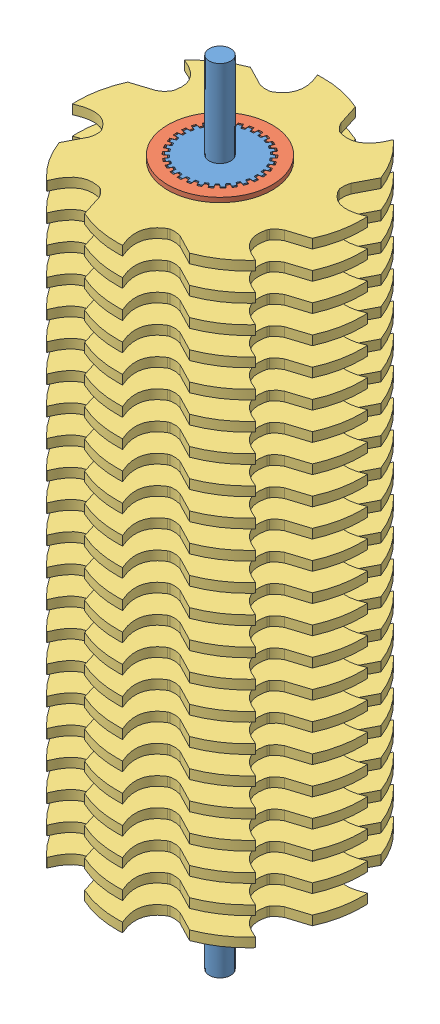
SolidWorks assembly Secondary Grinder Ungeared Blade Assembly, configuration Default. Lengths in mm.
Overall size (84.1 270.26 84.1).
46 component instances, 4 part files, 8 mates.
Components (placement in the parent):
- Secondary Grinder Ungeared Axle-1: Secondary Grinder Ungeared Axle [Default] at (84.7732 71.1932 255.0164) size (26.78 270.26 26.83)
- Secondary Grinder Thin Spacer-1: Secondary Grinder Thin Spacer [Default] at (84.7732 280.7432 255.0164) size (35.56 1.59 35.56)
- Secondary Grinder Blade-34: Secondary Grinder Blade [Default] at (84.7732 276.5099 255.0164) size (84.1 3.17 84.1)
- Secondary Grinder Spacer-34: Secondary Grinder Spacer [Default] at (84.7732 271.2182 255.0164) x (-0.809017 0 0.587785) z (-0.587785 0 -0.809017) size (35.56 6.35 35.56)
- Secondary Grinder Blade-35: Secondary Grinder Blade [Default] at (84.7732 266.9849 255.0164) size (84.1 3.17 84.1)
- Secondary Grinder Blade-36: Secondary Grinder Blade [Default] at (84.7732 257.4599 255.0164) size (84.1 3.17 84.1)
- Secondary Grinder Blade-37: Secondary Grinder Blade [Default] at (84.7732 247.9349 255.0164) size (84.1 3.17 84.1)
- Secondary Grinder Blade-38: Secondary Grinder Blade [Default] at (84.7732 238.4099 255.0164) size (84.1 3.17 84.1)
- Secondary Grinder Blade-39: Secondary Grinder Blade [Default] at (84.7732 228.8849 255.0164) size (84.1 3.17 84.1)
- Secondary Grinder Blade-40: Secondary Grinder Blade [Default] at (84.7732 219.3599 255.0164) size (84.1 3.17 84.1)
- Secondary Grinder Blade-41: Secondary Grinder Blade [Default] at (84.7732 209.8349 255.0164) size (84.1 3.17 84.1)
- Secondary Grinder Blade-42: Secondary Grinder Blade [Default] at (84.7732 200.3099 255.0164) size (84.1 3.17 84.1)
- Secondary Grinder Blade-43: Secondary Grinder Blade [Default] at (84.7732 190.7849 255.0164) size (84.1 3.17 84.1)
- Secondary Grinder Blade-44: Secondary Grinder Blade [Default] at (84.7732 181.2599 255.0164) size (84.1 3.17 84.1)
- Secondary Grinder Blade-45: Secondary Grinder Blade [Default] at (84.7732 171.7349 255.0164) size (84.1 3.17 84.1)
- Secondary Grinder Blade-46: Secondary Grinder Blade [Default] at (84.7732 162.2099 255.0164) size (84.1 3.17 84.1)
- Secondary Grinder Blade-47: Secondary Grinder Blade [Default] at (84.7732 152.6849 255.0164) size (84.1 3.17 84.1)
- Secondary Grinder Blade-48: Secondary Grinder Blade [Default] at (84.7732 143.1599 255.0164) size (84.1 3.17 84.1)
- Secondary Grinder Blade-49: Secondary Grinder Blade [Default] at (84.7732 133.6349 255.0164) size (84.1 3.17 84.1)
- Secondary Grinder Blade-50: Secondary Grinder Blade [Default] at (84.7732 124.1099 255.0164) size (84.1 3.17 84.1)
- Secondary Grinder Blade-51: Secondary Grinder Blade [Default] at (84.7732 114.5849 255.0164) size (84.1 3.17 84.1)
- Secondary Grinder Blade-52: Secondary Grinder Blade [Default] at (84.7732 105.0599 255.0164) size (84.1 3.17 84.1)
- Secondary Grinder Blade-53: Secondary Grinder Blade [Default] at (84.7732 95.5349 255.0164) size (84.1 3.17 84.1)
- Secondary Grinder Blade-54: Secondary Grinder Blade [Default] at (84.7732 86.0099 255.0164) size (84.1 3.17 84.1)
- Secondary Grinder Blade-55: Secondary Grinder Blade [Default] at (84.7732 76.4849 255.0164) size (84.1 3.17 84.1)
- Secondary Grinder Spacer-35: Secondary Grinder Spacer [Default] at (84.7732 261.6932 255.0164) x (-0.809017 0 0.587785) z (-0.587785 0 -0.809017) size (35.56 6.35 35.56)
- Secondary Grinder Spacer-36: Secondary Grinder Spacer [Default] at (84.7732 252.1682 255.0164) x (-0.809017 0 0.587785) z (-0.587785 0 -0.809017) size (35.56 6.35 35.56)
- Secondary Grinder Spacer-37: Secondary Grinder Spacer [Default] at (84.7732 242.6432 255.0164) x (-0.809017 0 0.587785) z (-0.587785 0 -0.809017) size (35.56 6.35 35.56)
- Secondary Grinder Spacer-38: Secondary Grinder Spacer [Default] at (84.7732 233.1182 255.0164) x (-0.809017 0 0.587785) z (-0.587785 0 -0.809017) size (35.56 6.35 35.56)
- Secondary Grinder Spacer-39: Secondary Grinder Spacer [Default] at (84.7732 223.5932 255.0164) x (-0.809017 0 0.587785) z (-0.587785 0 -0.809017) size (35.56 6.35 35.56)
- Secondary Grinder Spacer-40: Secondary Grinder Spacer [Default] at (84.7732 214.0682 255.0164) x (-0.809017 0 0.587785) z (-0.587785 0 -0.809017) size (35.56 6.35 35.56)
- Secondary Grinder Spacer-41: Secondary Grinder Spacer [Default] at (84.7732 204.5432 255.0164) x (-0.809017 0 0.587785) z (-0.587785 0 -0.809017) size (35.56 6.35 35.56)
- Secondary Grinder Spacer-42: Secondary Grinder Spacer [Default] at (84.7732 195.0182 255.0164) x (-0.809017 0 0.587785) z (-0.587785 0 -0.809017) size (35.56 6.35 35.56)
- Secondary Grinder Spacer-43: Secondary Grinder Spacer [Default] at (84.7732 185.4932 255.0164) x (-0.809017 0 0.587785) z (-0.587785 0 -0.809017) size (35.56 6.35 35.56)
- Secondary Grinder Spacer-44: Secondary Grinder Spacer [Default] at (84.7732 175.9682 255.0164) x (-0.809017 0 0.587785) z (-0.587785 0 -0.809017) size (35.56 6.35 35.56)
- Secondary Grinder Spacer-45: Secondary Grinder Spacer [Default] at (84.7732 166.4432 255.0164) x (-0.809017 0 0.587785) z (-0.587785 0 -0.809017) size (35.56 6.35 35.56)
- Secondary Grinder Spacer-46: Secondary Grinder Spacer [Default] at (84.7732 156.9182 255.0164) x (-0.809017 0 0.587785) z (-0.587785 0 -0.809017) size (35.56 6.35 35.56)
- Secondary Grinder Spacer-47: Secondary Grinder Spacer [Default] at (84.7732 147.3932 255.0164) x (-0.809017 0 0.587785) z (-0.587785 0 -0.809017) size (35.56 6.35 35.56)
- Secondary Grinder Spacer-48: Secondary Grinder Spacer [Default] at (84.7732 137.8682 255.0164) x (-0.809017 0 0.587785) z (-0.587785 0 -0.809017) size (35.56 6.35 35.56)
- Secondary Grinder Spacer-49: Secondary Grinder Spacer [Default] at (84.7732 128.3432 255.0164) x (-0.809017 0 0.587785) z (-0.587785 0 -0.809017) size (35.56 6.35 35.56)
- Secondary Grinder Spacer-50: Secondary Grinder Spacer [Default] at (84.7732 118.8182 255.0164) x (-0.809017 0 0.587785) z (-0.587785 0 -0.809017) size (35.56 6.35 35.56)
- Secondary Grinder Spacer-51: Secondary Grinder Spacer [Default] at (84.7732 109.2932 255.0164) x (-0.809017 0 0.587785) z (-0.587785 0 -0.809017) size (35.56 6.35 35.56)
- Secondary Grinder Spacer-52: Secondary Grinder Spacer [Default] at (84.7732 99.7682 255.0164) x (-0.809017 0 0.587785) z (-0.587785 0 -0.809017) size (35.56 6.35 35.56)
- Secondary Grinder Spacer-53: Secondary Grinder Spacer [Default] at (84.7732 90.2432 255.0164) x (-0.809017 0 0.587785) z (-0.587785 0 -0.809017) size (35.56 6.35 35.56)
- Secondary Grinder Spacer-54: Secondary Grinder Spacer [Default] at (84.7732 80.7182 255.0164) x (-0.809017 0 0.587785) z (-0.587785 0 -0.809017) size (35.56 6.35 35.56)
- Secondary Grinder Spacer-55: Secondary Grinder Spacer [Default] at (84.7732 71.1932 255.0164) x (-0.809017 0 0.587785) z (-0.587785 0 -0.809017) size (35.56 6.35 35.56)
Mates (geometry in assembly coordinates):
- Coincident1: coincident aligned: plane of Secondary Grinder Ungeared Axle-1 through (84.7732 282.3307 255.0164) normal (0 1 0); plane of Secondary Grinder Thin Spacer-1 through (84.7732 282.3307 255.0164) normal (0 1 0)
- Concentric1: concentric aligned: circle of Secondary Grinder Ungeared Axle-1; circle of Secondary Grinder Thin Spacer-1
- Parallel2: parallel anti-aligned: line of Secondary Grinder Ungeared Axle-1 through (96.9536 282.3307 254.4846) axis (0.982609 0 -0.185685); line of Secondary Grinder Thin Spacer-1 through (98.7207 282.3307 254.2244) axis (-0.982609 0 0.185685)
- Coincident4: coincident anti-aligned: plane of Secondary Grinder Thin Spacer-1 through (84.7732 280.7432 255.0164) normal (0 -1 0); plane of Secondary Grinder Blade-34 through (71.0611 280.7432 226.2364) normal (0 1 0)
- Coincident5: coincident aligned: line of Secondary Grinder Thin Spacer-1 through (94.6944 280.7432 245.1813) axis (-0.795485 0 0.605973); line of Secondary Grinder Blade-34 through (94.6944 280.7432 245.1813) axis (-0.795485 0 0.605973)
- Coincident6: coincident aligned: line of Secondary Grinder Thin Spacer-1 through (76.029 280.7432 265.9114) axis (0.519503 0 -0.854469); line of Secondary Grinder Blade-34 through (76.029 280.7432 265.9114) axis (0.519503 0 -0.854469)
- Concentric2: concentric aligned: cylinder of Secondary Grinder Ungeared Axle-1 through (84.7732 311.89 255.0164) axis (0 -1 0) radius 3.6805; cylinder of Secondary Grinder Spacer-34 through (84.7732 277.5682 255.0164) axis (0 -1 0) radius 17.78
- Coincident8: coincident aligned: line of Secondary Grinder Blade-34 through (97.1927 277.5682 261.4129) axis (-0.822133 0 -0.569295); line of Secondary Grinder Spacer-34 through (97.1927 277.5682 261.4129) axis (-0.822133 0 -0.569295)
